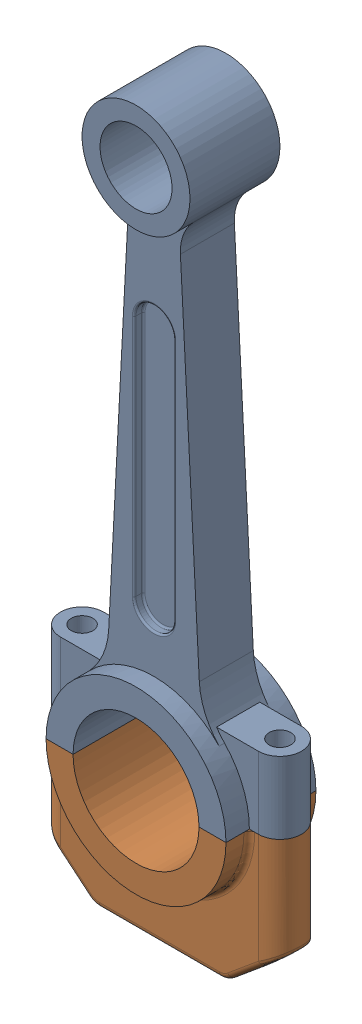
SolidWorks assembly connectingrodassemble, configuration 默认. Lengths in mm.
Overall size (134 410 50).
2 component instances, 2 part files, 3 mates.
Components (placement in the parent):
- connectingrod-1: connectingrod [默认] at (-70.0479 144.7794 25) size (134 330 50)
- connectingrodnut-1: connectingrodnut [默认] at (-70.0479 -155.2206 25) x (1 0 0) z (0 0 -1) size (134 80 50)
Mates (geometry in assembly coordinates):
- 同心1: concentric: cylinder of 连杆-1 through (-15.0479 -155.2206 25) axis (0 1 0) radius 6; cylinder of 连杆帽-1 through (-15.0479 -235.2206 25) axis (0 1 0) radius 6
- 同心2: concentric: cylinder of 连杆-1 through (-125.0479 -155.2206 25) axis (0 1 0) radius 6; cylinder of 连杆帽-1 through (-125.0479 -235.2206 25) axis (0 1 0) radius 6
- 重合1: coincident anti-aligned: plane of 连杆-1 through (-70.0479 -155.2206 50) normal (0 -1 0); plane of 连杆帽-1 through (-120.0479 -155.2206 0) normal (0 1 0)
